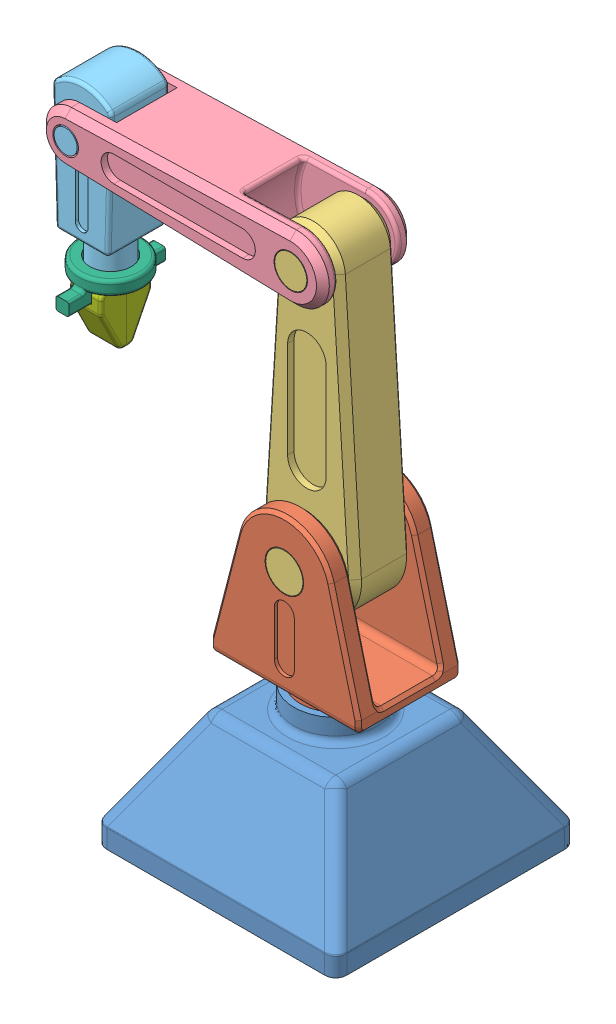
SolidWorks assembly RobotArm, configuration Default. Lengths in mm.
Overall size (937.56 1269.77 499.06).
8 component instances, 7 part files, 18 mates.
Components (placement in the parent):
- Base-1: Base [Default] at (95.6422 507.7709 301.4973) size (375.12 215 375.12)
- Link_1-1: Link_1 [Default] at (95.6422 507.7709 301.4973) size (230 280 160)
- Link_2-2: Link_2 [Default] at (95.6422 507.7709 301.4973) size (150 525 160)
- Link_3-1: Link_3 [Default] at (95.6422 507.7709 301.4973) size (440 100 140)
- Link_4-1: Link_4 [Default] at (145.6422 1257.7709 301.4973) x (0 1 0) z (0 0 1) size (265 92.4 140)
- Link_5-1: Link_5 [Default] at (145.6422 1259.7709 301.4973) x (0 1 0) z (0 0 1) size (42 100 150)
- link_6-1: link_6 [Default] at (145.6422 1259.7709 301.4973) x (0 1 0) z (0 0 1) size (90 50 40)
- link_6-2: link_6 [Default] at (-654.3578 1259.7709 301.4973) x (0 1 0) z (0 0 -1) size (90 50 40)
Mates (geometry in assembly coordinates):
- Concentric1: concentric anti-aligned: cylinder of Base-1 through (95.6422 317.7709 301.4973) axis (0 -1 0) radius 55; cylinder of Link_1-1 through (95.6422 302.7709 301.4973) axis (0 1 0) radius 55
- Coincident1: coincident anti-aligned: plane of Base-1 through (95.6422 302.7709 301.4973) normal (0 1 0); plane of Link_1-1 through (95.6422 302.7709 301.4973) normal (0 -1 0)
- Concentric3: concentric aligned: cylinder of Link_1-1 through (95.6422 507.7709 221.4973) axis (0 0 1) radius 30; cylinder of Link_2-2 through (95.6422 507.7709 139.4729) axis (0 0 1) radius 29
- Coincident3: coincident aligned: plane of Link_1-1 through (-19.3578 342.7709 221.4973) normal (0 0 -1); plane of Link_2-2 through (-19.3578 342.7709 221.4973) normal (0 0 -1)
- Concentric5: concentric anti-aligned: cylinder of Link_2-2 through (95.6422 907.7709 371.4973) axis (0 0 -1) radius 25; cylinder of Link_3-1 through (95.6422 907.7709 -219.7232) axis (0 0 1) radius 26
- Coincident5: coincident aligned: plane of Link_2-2 through (95.6422 907.7709 231.4973) normal (0 0 -1); plane of Link_3-1 through (95.6422 907.7709 231.4973) normal (0 0 -1)
- Concentric6: concentric anti-aligned: cylinder of Link_3-1 through (-254.3578 907.7709 -219.7232) axis (0 0 1) radius 20; cylinder of Link_4-1 through (-254.3578 907.7709 422.409) axis (0 0 -1) radius 18
- Coincident6: coincident aligned: plane of Link_3-1 through (95.6422 907.7709 231.4973) normal (0 0 -1); plane of Link_4-1 through (-254.3578 1257.7709 231.4973) normal (0 0 -1)
- Concentric7: concentric anti-aligned: cylinder of Link_4-1 through (-254.3578 707.7709 301.4973) axis (0 1 0) radius 30; cylinder of Link_5-1 through (-254.3578 719.7709 301.4973) axis (0 -1 0) radius 32
- Coincident7: coincident anti-aligned: plane of Link_4-1 through (-254.3578 707.7709 301.4973) normal (0 -1 0); plane of Link_5-1 through (-254.3578 707.7709 301.4973) normal (0 1 0)
- Coincident8: coincident anti-aligned: plane of Link_5-1 through (-244.3578 677.7709 226.4973) normal (1 0 0); plane of link_6-1 through (-244.3578 1259.7709 261.4973) normal (-1 0 0)
- Coincident9: coincident anti-aligned: plane of Link_5-1 through (145.6422 677.7709 301.4973) normal (0 -1 0); plane of link_6-1 through (145.6422 677.7709 261.4973) normal (0 1 0)
- Parallel1: parallel aligned: plane of Base-1 through (264.9243 102.7709 488.0999) normal (0 0 1); plane of Link_1-1 through (95.6422 507.7709 381.4973) normal (0 0 1)
- Parallel2: parallel aligned: plane of Link_1-1 through (111.2827 382.7709 376.4973) normal (-1 0 0); plane of Link_2-2 through (125.6422 782.7709 336.4973) normal (-1 0 0)
- Perpendicular1: perpendicular: plane of Link_2-2 through (125.6422 782.7709 336.4973) normal (-1 0 0); plane of Link_3-1 through (-179.3578 887.7709 361.4973) normal (0 1 0)
- Perpendicular2: perpendicular: plane of Link_3-1 through (-179.3578 887.7709 361.4973) normal (0 1 0); plane of Link_4-1 through (-244.3578 782.7709 341.4973) normal (-1 0 0)
- Parallel12: parallel aligned: plane of Link_4-1 through (-264.3578 782.7709 341.4973) normal (1 0 0); plane of Link_5-1 through (-244.3578 677.7709 226.4973) normal (1 0 0)
- Coincident23: coincident aligned: plane of Link_5-1 through (145.6422 1259.7709 301.4973) normal (0 0 1); plane of link_6-1 through (145.6422 1259.7709 301.4973) normal (0 0 1)
